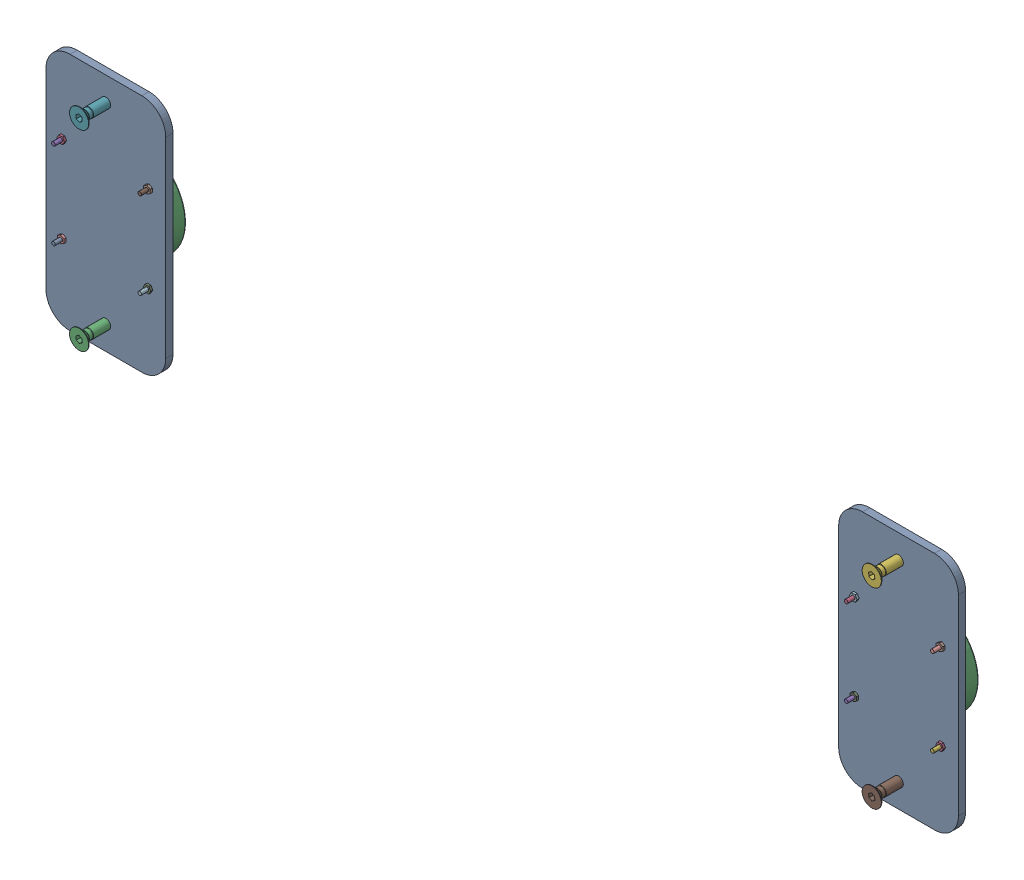
SolidWorks assembly ARMSET-PART, configuration Défaut. Lengths in mm.
Overall size (761.94 200 51.36).
28 component instances, 6 part files, 10 mates.
Components (placement in the parent):
- ARMSET-PLATE-1: ARMSET-PLATE [Défaut] at (129.2844 -62.1488 0) size (100 200 6)
- EX 80 S-1: EX 80 S [Défaut] at (25.2938 -63.0086 -1002.35) size (80 98.5 23)
- ecrou_iso_4036_m3-1: ecrou_iso_4036_m3 [Default] at (-37.3494 32.3811 6) size (6.35 5.5 1.8)
- vis_uni_5933_m3x16-a2_0-1: vis_uni_5933_m3x16-a2_0 [Default] at (-37.3494 32.3811 -0.5) x (0.86877 -0.495216 0) z (0 0 1) size (6 6 16)
- ecrou_din934_m8-10-1: ecrou_din934_m8-10 [Default] at (-1.3494 76.3811 -6.5) size (15.01 13 6.83)
- vis_uni_5933_m8x40-10_9_0-1: vis_uni_5933_m8x40-10_9_0 [Default] at (-1.3494 76.3811 23.96) x (-0.809528 -0.587081 0) z (0 0 -1) size (16 16 40)
- ecrou_iso_4036_m3-2: ecrou_iso_4036_m3 [Default] at (34.6794 32.4099 6) x (0 -1 0) z (0 0 1) size (6.35 5.5 1.8)
- ecrou_iso_4036_m3-3: ecrou_iso_4036_m3 [Default] at (34.7081 -39.6189 6) x (-1 0 0) z (0 0 1) size (6.35 5.5 1.8)
- ecrou_iso_4036_m3-4: ecrou_iso_4036_m3 [Default] at (-37.3206 -39.6476 6) x (0 1 0) z (0 0 1) size (6.35 5.5 1.8)
- vis_uni_5933_m3x16-a2_0-2: vis_uni_5933_m3x16-a2_0 [Default] at (34.6794 32.4099 -0.5) x (-0.495216 -0.86877 0) z (0 0 1) size (6 6 16)
- vis_uni_5933_m3x16-a2_0-3: vis_uni_5933_m3x16-a2_0 [Default] at (34.7081 -39.6189 -0.5) x (-0.86877 0.495216 0) z (0 0 1) size (6 6 16)
- vis_uni_5933_m3x16-a2_0-4: vis_uni_5933_m3x16-a2_0 [Default] at (-37.3206 -39.6476 -0.5) x (0.495216 0.86877 0) z (0 0 1) size (6 6 16)
- ecrou_din934_m8-10-2: ecrou_din934_m8-10 [Default] at (-1.3494 -83.6189 -6.5) size (15.01 13 6.83)
- vis_uni_5933_m8x40-10_9_0-2: vis_uni_5933_m8x40-10_9_0 [Default] at (-1.3494 -83.6189 23.96) x (-0.809528 -0.587081 0) z (0 0 -1) size (16 16 40)
- ecrou_iso_4036_m3-5: ecrou_iso_4036_m3 [Default] at (696.6481 -39.6189 6) x (-1 0 0) z (0 0 1) size (6.35 5.5 1.8)
- vis_uni_5933_m3x16-a2_0-5: vis_uni_5933_m3x16-a2_0 [Default] at (624.6194 -39.6476 -0.5) x (0.495216 0.86877 0) z (0 0 1) size (6 6 16)
- vis_uni_5933_m3x16-a2_0-6: vis_uni_5933_m3x16-a2_0 [Default] at (696.6481 -39.6189 -0.5) x (-0.86877 0.495216 0) z (0 0 1) size (6 6 16)
- ecrou_din934_m8-10-3: ecrou_din934_m8-10 [Default] at (660.5906 -83.6189 -6.5) size (15.01 13 6.83)
- ecrou_iso_4036_m3-6: ecrou_iso_4036_m3 [Default] at (696.6194 32.4099 6) x (0 -1 0) z (0 0 1) size (6.35 5.5 1.8)
- ecrou_iso_4036_m3-7: ecrou_iso_4036_m3 [Default] at (624.6194 -39.6476 6) x (0 1 0) z (0 0 1) size (6.35 5.5 1.8)
- vis_uni_5933_m3x16-a2_0-7: vis_uni_5933_m3x16-a2_0 [Default] at (696.6194 32.4099 -0.5) x (-0.495216 -0.86877 0) z (0 0 1) size (6 6 16)
- vis_uni_5933_m8x40-10_9_0-3: vis_uni_5933_m8x40-10_9_0 [Default] at (660.5906 -83.6189 23.96) x (-0.809528 -0.587081 0) z (0 0 -1) size (16 16 40)
- ecrou_iso_4036_m3-8: ecrou_iso_4036_m3 [Default] at (624.5906 32.3811 6) size (6.35 5.5 1.8)
- ARMSET-PLATE-2: ARMSET-PLATE [Défaut] at (791.2244 -62.1488 0) size (100 200 6)
- EX 80 S-2: EX 80 S [Défaut] at (687.2338 -63.0086 -1002.35) size (80 98.5 23)
- vis_uni_5933_m3x16-a2_0-8: vis_uni_5933_m3x16-a2_0 [Default] at (624.5906 32.3811 -0.5) x (0.86877 -0.495216 0) z (0 0 1) size (6 6 16)
- ecrou_din934_m8-10-4: ecrou_din934_m8-10 [Default] at (660.5906 76.3811 -6.5) size (15.01 13 6.83)
- vis_uni_5933_m8x40-10_9_0-4: vis_uni_5933_m8x40-10_9_0 [Default] at (660.5906 76.3811 23.96) x (-0.809528 -0.587081 0) z (0 0 -1) size (16 16 40)
Mates (geometry in assembly coordinates):
- Coïncidente1: coincident anti-aligned: plane of 250312-NIM-HEAT-ARMSET-PLATE-1 through (129.2844 -62.1488 0) normal (0 0 -1); plane of EX 80 S-1 through (4.313 2.5968 0) normal (0 0 1)
- Coaxiale1: concentric aligned: cylinder of 250312-NIM-HEAT-ARMSET-PLATE-1 through (34.6506 32.3811 -11.3137) axis (0 0 1) radius 2; cylinder of EX 80 S-1 through (34.6506 32.3811 -2) axis (0 0 1) radius 2.5
- Coaxiale3: concentric anti-aligned: cylinder of 250312-NIM-HEAT-ARMSET-PLATE-1 through (-37.3494 32.3811 -11.3137) axis (0 0 1) radius 2; cylinder of vis_uni_5933_m3x16-a2_0-1 through (-37.3494 32.3811 7.15) axis (0 0 -1) radius 1.5
- Coïncidente3: coincident anti-aligned: plane of EX 80 S-1 through (4.313 2.5968 -2) normal (0 0 -1); circle of vis_uni_5933_m3x16-a2_0-1
- Coaxiale5: concentric aligned: cylinder of ecrou_iso_4036_m3-1 through (-37.3494 32.3811 6.9) axis (0 0 -1) radius 1.2294; cylinder of vis_uni_5933_m3x16-a2_0-1 through (-37.3494 32.3811 7.15) axis (0 0 -1) radius 1.5
- Coïncidente4: coincident anti-aligned: plane of 250312-NIM-HEAT-ARMSET-PLATE-1 through (129.2844 -62.1488 6) normal (0 0 1); plane of ecrou_iso_4036_m3-1 through (-37.3494 32.3811 6) normal (0 0 -1)
- Coaxiale8: concentric aligned: cylinder of 250312-NIM-HEAT-ARMSET-PLATE-1 through (-1.3494 76.3811 -11.3137) axis (0 0 1) radius 4; cylinder of vis_uni_5933_m8x40-10_9_0-1 through (-1.3494 76.3811 4.6233) axis (0 0 1) radius 4
- Distance2: distance = 28.36 mm anti-aligned: plane of vis_uni_5933_m8x40-10_9_0-1 through (0.9989 73.143 28.36) normal (0 0 1); plane of 250312-NIM-HEAT-ARMSET-PLATE-1 through (129.2844 -62.1488 0) normal (0 0 -1)
- Coaxiale9: concentric anti-aligned: cylinder of ecrou_din934_m8-10-1 through (-1.3494 76.3811 -3.25) axis (0 0 -1) radius 3.3234; cylinder of vis_uni_5933_m8x40-10_9_0-1 through (-1.3494 76.3811 4.6233) axis (0 0 1) radius 4
- Coïncidente9: coincident anti-aligned: plane of 250312-NIM-HEAT-ARMSET-PLATE-1 through (129.2844 -62.1488 0) normal (0 0 -1); plane of ecrou_din934_m8-10-1 through (-1.3494 76.3811 0) normal (0 0 1)
